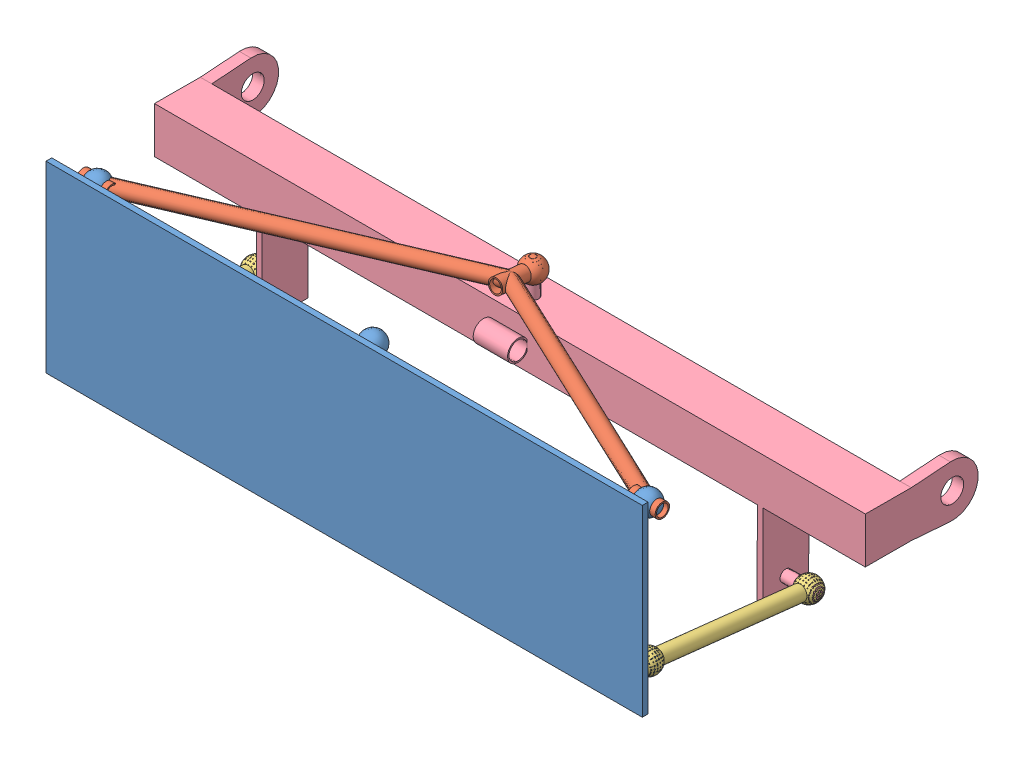
SolidWorks assembly rearsusptest, configuration Default. Lengths in mm.
Overall size (787.4 220.57 308.71).
6 component instances, 5 part files, 9 mates.
Components (placement in the parent):
- rearsuspplate-1: rearsuspplate [Default] at origin size (660.4 203.2 44.45)
- rearsusptriangle-1: rearsusptriangle [Default<As Machined>] at (0 76.2 -25.4) x (1 0 0) z (0 -0.098528 -0.995134) size (641.35 25.4 198.83)
- Part6^rearsusptest-1: Part6^rearsusptest [Default] at origin (virtual)
- rearsusplink-1: rearsusplink [Default<As Machined>] at (304.8 -76.2 -25.4) x (0.436399 -0.894534 0.096774) z (-0.006429 0.104453 0.994509) size (25.4 25.4 203.2)
- rearsusplink-2: rearsusplink [Default<As Machined>] at (-304.8 -76.2 -25.4) x (0.987765 0.154302 -0.022591) z (0.006429 0.104453 0.994509) size (25.4 25.4 203.2)
- rearsuspbar-1: rearsuspbar [Default] at (0 7.8437 -202.5569) x (-1 0 0) z (0 0.003247 0.999995) size (787.4 189.99 146.61)
Mates (geometry in assembly coordinates):
- Concentric1: concentric: sphere of rearsuspplate-1; cylinder of rearsusptriangle-1 through (288.925 76.2 -25.4) axis (1 0 0) radius 6.4643
- Concentric3: concentric: sphere of rearsuspplate-1; cylinder of rearsusptriangle-1 through (-320.675 76.2 -25.4) axis (1 0 0) radius 6.4643
- Coincident1: coincident: line of rearsusptriangle-1 through (0 59.8947 -190.0837) axis (0 -0.098528 -0.995134)
- Concentric4: concentric: sphere of rearsuspplate-1; sphere of rearsusplink-1
- Concentric5: concentric: sphere of rearsuspplate-1; sphere of rearsusplink-2
- Concentric6: concentric: sphere of rearsusptriangle-1; sphere of rearsuspbar-1
- Concentric7: concentric: sphere of rearsusplink-2; sphere of rearsuspbar-1
- Concentric8: concentric: sphere of rearsusplink-1; sphere of rearsuspbar-1
- Parallel8: parallel: line of rearsuspbar-1 through (-381 33.161 -228.0393) axis (1 0 0)
